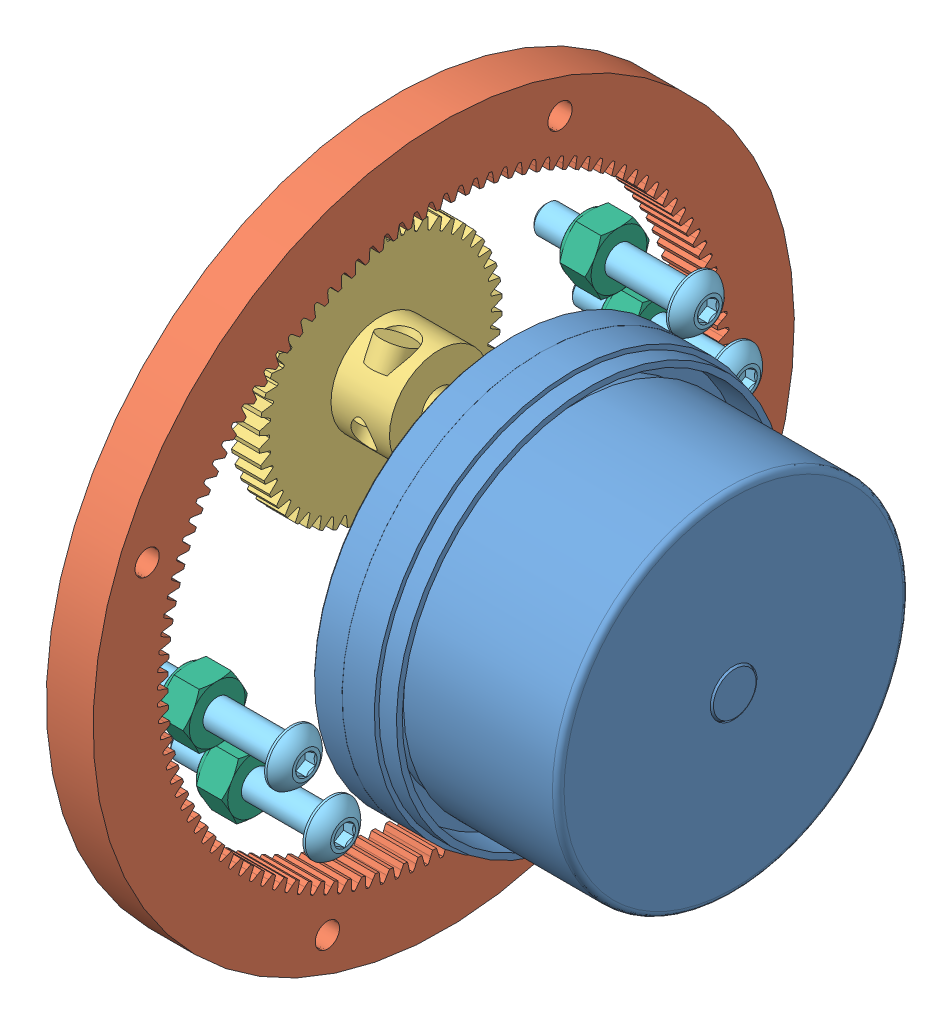
SolidWorks assembly Motor and Gear, configuration Default. Lengths in mm.
Overall size (63.6 155.53 155.53).
14 component instances, 7 part files, 31 mates.
Components (placement in the parent):
- EC60 Motor-1: EC60 Motor [Default] at (-25.8141 57.1537 61.758) x (1 0 0) z (0 -0.623002 -0.78222) size (61.3 68 68)
- Ring Gear-1: Ring Gear [Default] at (-41.4141 57.1537 61.758) x (1 0 0) z (0 -0.930938 0.365178) size (8 120 120)
- Planetary Gear-1: Planetary Gear [Default] at (-41.4141 30.7389 52.4704) x (0 0.993412 0.114594) z (1 0 0) size (41.56 41.6 15)
- Planetary Gear-2: Planetary Gear [Default] at (-41.4141 83.5685 71.0455) x (0 0.901032 -0.433752) z (1 0 0) size (41.56 41.6 15)
- Sun Gear-1: Sun Gear [Default] at (-41.4141 57.1537 61.758) x (1 0 0) z (0 0.107045 -0.994254) size (12.02 17.63 17.63)
- Shaft_Carrier_Combined-1: Shaft_Carrier_Combined [Default] at (-54.6266 57.1537 61.758) x (0 -0.902317 -0.431074) z (0 0.431074 -0.902317) size (91.44 66.28 91.44) (hidden)
- 10-32 Button Cap Screw-1: 10-32 Button Cap Screw [92949A271] at (-23.2487 80.4533 30.6645) x (0 0 -1) z (1 0 0) size (9.17 9.17 28.15)
- 10-32 Button Cap Screw-2: 10-32 Button Cap Screw [92949A271] at (-23.2487 47.6055 99.421) x (0 0 -1) z (1 0 0) size (9.17 9.17 28.15)
- 10-32 Button Cap Screw-3: 10-32 Button Cap Screw [92949A271] at (-23.2487 33.8542 92.8514) x (0 0 -1) z (1 0 0) size (9.17 9.17 28.15)
- 10-32 Button Cap Screw-4: 10-32 Button Cap Screw [92949A271] at (-23.2487 66.702 24.0949) x (0 0 -1) z (1 0 0) size (9.17 9.17 28.15)
- 10-32 Thread Locking Nut-1: 10-32 Thread Locking Nut [90631A411] at (-38.5141 33.8542 92.8514) x (0 0.999473 -0.032461) z (0 0.032461 0.999473) size (9.53 6.11 11)
- 10-32 Thread Locking Nut-2: 10-32 Thread Locking Nut [90631A411] at (-38.5141 47.6055 99.421) x (0 1 0) z (0 0 1) size (9.53 6.11 11)
- 10-32 Thread Locking Nut-3: 10-32 Thread Locking Nut [90631A411] at (-38.5141 66.702 24.0949) x (0 0.993687 -0.112192) z (0 0.112192 0.993687) size (9.53 6.11 11)
- 10-32 Thread Locking Nut-4: 10-32 Thread Locking Nut [90631A411] at (-38.5141 80.4533 30.6645) x (0 1 0) z (0 0 1) size (9.53 6.11 11)
Mates (geometry in assembly coordinates):
- Concentric2: concentric: cylinder of EC60 Motor-1 through (-48.9141 57.1537 61.758) axis (1 0 0) radius 4; point of Ring Gear-1
- Concentric4: concentric anti-aligned: cylinder of EC60 Motor-1 through (-48.9141 57.1537 61.758) axis (1 0 0) radius 4; cylinder of Sun Gear-1 through (-31.3141 57.1537 61.758) axis (-1 0 0) radius 4
- Distance1: distance = 5 mm aligned: plane of Sun Gear-1 through (-43.9141 57.1537 61.758) normal (-1 0 0); plane of EC60 Motor-1 through (-48.9141 54.5668 63.8183) normal (-1 0 0)
- Coincident2: coincident aligned: plane of Ring Gear-1; plane of Sun Gear-1
- Coincident3: coincident aligned: plane of Planetary Gear-1 through (-41.4141 30.7389 52.4704) normal (1 0 0); plane of Sun Gear-1
- Coincident4: coincident aligned: plane of Planetary Gear-2 through (-41.4141 83.5685 71.0455) normal (1 0 0); plane of Sun Gear-1
- Distance2: distance = 28 mm: line of EC60 Motor-1 through (-47.4461 57.1537 61.758) axis (1 0 0); point of Planetary Gear-1
- Distance3: distance = 56 mm: point of Planetary Gear-2; point of Planetary Gear-1
- Distance4: distance = 28 mm: point of Planetary Gear-2; line of EC60 Motor-1 through (-47.4461 57.1537 61.758) axis (1 0 0)
- Concentric5: concentric aligned: line of EC60 Motor-1 through (-47.4461 57.1537 61.758) axis (1 0 0); cylinder of Shaft_Carrier_Combined-1 through (-59.7066 57.1537 61.758) axis (1 0 0) radius 6.35
- Distance5: distance = 6.35 mm anti-aligned: plane of Shaft_Carrier_Combined-1 through (-32.1641 57.1537 61.758) normal (1 0 0); plane of EC60 Motor-1 through (-25.8141 30.5582 82.94) normal (-1 0 0)
- Parallel1: parallel aligned: cylinder of Planetary Gear-1 through (-28.1641 30.7389 52.4704) axis (-1 0 0) radius 8.5; cylinder of Shaft_Carrier_Combined-1 through (-48.0391 31.8888 49.6879) axis (-1 0 0) radius 3
- GearMate1: gear = 20 : 50 mm: cylinder of Planetary Gear-2 through (-28.1641 83.5685 71.0455) axis (-1 0 0) radius 8.5; cylinder of Sun Gear-1 through (-41.8891 57.1537 61.758) axis (1 0 0) radius 5
- GearMate2: gear = 50 : 20 mm: cylinder of Sun Gear-1 through (-41.8891 57.1537 61.758) axis (1 0 0) radius 5; cylinder of Planetary Gear-1 through (-28.1641 30.7389 52.4704) axis (-1 0 0) radius 8.5
- GearMate5: gear = 120 : 50 mm: cylinder of Planetary Gear-2 through (-28.1641 83.5685 71.0455) axis (-1 0 0) radius 8.5; cylinder of Ring Gear-1 through (-45.4141 57.1537 61.758) axis (1 0 0) radius 60
- Concentric16: concentric anti-aligned: cylinder of Shaft_Carrier_Combined-1 through (-61.3618 33.8542 92.8514) axis (1 0 0) radius 2.3813; cylinder of 10-32 Button Cap Screw-3 through (-51.2141 33.8542 92.8514) axis (-1 0 0) radius 2.413
- Concentric17: concentric anti-aligned: cylinder of Shaft_Carrier_Combined-1 through (-61.3618 47.6055 99.421) axis (1 0 0) radius 2.3813; cylinder of 10-32 Button Cap Screw-2 through (-51.2141 47.6055 99.421) axis (-1 0 0) radius 2.413
- Concentric18: concentric anti-aligned: cylinder of Shaft_Carrier_Combined-1 through (-61.3618 80.4533 30.6645) axis (1 0 0) radius 2.3813; cylinder of 10-32 Button Cap Screw-1 through (-51.2141 80.4533 30.6645) axis (-1 0 0) radius 2.413
- Concentric19: concentric anti-aligned: cylinder of Shaft_Carrier_Combined-1 through (-61.3618 66.702 24.0949) axis (1 0 0) radius 2.3813; cylinder of 10-32 Button Cap Screw-4 through (-51.2141 66.702 24.0949) axis (-1 0 0) radius 2.413
- Coincident7: coincident aligned: plane of EC60 Motor-1 through (-25.8141 30.5582 82.94) normal (-1 0 0); plane of 10-32 Button Cap Screw-2 through (-25.8141 43.0208 99.421) normal (-1 0 0)
- Coincident8: coincident aligned: plane of EC60 Motor-1 through (-25.8141 30.5582 82.94) normal (-1 0 0); plane of 10-32 Button Cap Screw-3 through (-25.8141 29.2695 92.8514) normal (-1 0 0)
- Coincident9: coincident aligned: plane of EC60 Motor-1 through (-25.8141 30.5582 82.94) normal (-1 0 0); plane of 10-32 Button Cap Screw-1 through (-25.8141 75.8686 30.6645) normal (-1 0 0)
- Coincident10: coincident aligned: plane of EC60 Motor-1 through (-25.8141 30.5582 82.94) normal (-1 0 0); plane of 10-32 Button Cap Screw-4 through (-25.8141 62.1173 24.0949) normal (-1 0 0)
- Concentric20: concentric anti-aligned: cylinder of 10-32 Button Cap Screw-3 through (-51.2141 33.8542 92.8514) axis (-1 0 0) radius 2.413; line of 10-32 Thread Locking Nut-1 through (-44.2386 33.8542 92.8514) axis (1 0 0)
- Coincident11: coincident anti-aligned: plane of Shaft_Carrier_Combined-1 through (-38.5141 57.1537 61.758) normal (-1 0 0); plane of 10-32 Thread Locking Nut-1 through (-38.5141 33.6756 87.3551) normal (1 0 0)
- Coincident12: coincident anti-aligned: plane of Shaft_Carrier_Combined-1 through (-38.5141 57.1537 61.758) normal (-1 0 0); plane of 10-32 Thread Locking Nut-2 through (-38.5141 47.6055 93.9217) normal (1 0 0)
- Coincident13: coincident anti-aligned: plane of Shaft_Carrier_Combined-1 through (-38.5141 57.1537 61.758) normal (-1 0 0); plane of 10-32 Thread Locking Nut-3 through (-38.5141 66.085 18.6304) normal (1 0 0)
- Coincident14: coincident anti-aligned: plane of Shaft_Carrier_Combined-1 through (-38.5141 57.1537 61.758) normal (-1 0 0); plane of 10-32 Thread Locking Nut-4 through (-38.5141 80.4533 25.1652) normal (1 0 0)
- Concentric21: concentric anti-aligned: cylinder of 10-32 Button Cap Screw-2 through (-51.2141 47.6055 99.421) axis (-1 0 0) radius 2.413; line of 10-32 Thread Locking Nut-2 through (-44.2386 47.6055 99.421) axis (1 0 0)
- Concentric22: concentric anti-aligned: cylinder of 10-32 Button Cap Screw-4 through (-51.2141 66.702 24.0949) axis (-1 0 0) radius 2.413; line of 10-32 Thread Locking Nut-3 through (-44.2386 66.702 24.0949) axis (1 0 0)
- Concentric23: concentric anti-aligned: cylinder of 10-32 Button Cap Screw-1 through (-51.2141 80.4533 30.6645) axis (-1 0 0) radius 2.413; line of 10-32 Thread Locking Nut-4 through (-44.2386 80.4533 30.6645) axis (1 0 0)
